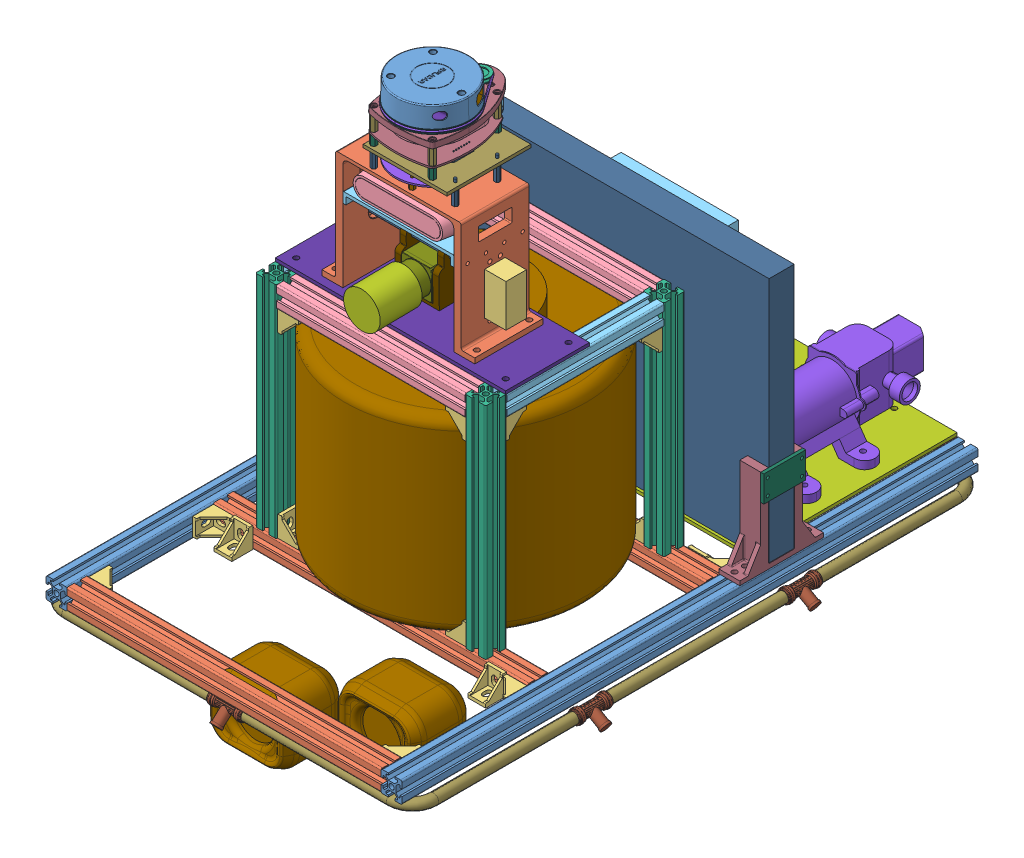
SolidWorks assembly 负载部分, configuration 默认. Lengths in mm.
Overall size (383.73 464.78 581.19).
141 component instances, 63 part files, 41 mates.
Components (placement in the parent):
- 外框架-1: 外框架 [默认] at (34.5366 78.9992 0) size (340 230 550)
  - 20x20-550mm-1: 20x20-550mm [默认] at (125.4634 0 -275) x (-1 0 0) z (0 0 -1) size (20 20 550)
  - 20x20-550mm-2: 20x20-550mm [默认] at (-194.5366 0 -275) x (-1 0 0) z (0 0 -1) size (20 20 550)
  - 20x20-300mm-1: 20x20-300mm [默认] at (115.4634 0 -265) x (0 0 -1) z (1 0 0) size (20 20 300)
  - 20x20-300mm-2: 20x20-300mm [默认] at (115.4634 0 265) x (0 0 -1) z (1 0 0) size (20 20 300)
  - 20x20-300mm-4: 20x20-300mm [默认] at (115.4634 0 125) x (0 0 -1) z (1 0 0) size (20 20 300)
  - 20x20-300mm-5: 20x20-300mm [默认] at (115.4634 0 -45) x (0 0 -1) z (1 0 0) size (20 20 300)
  - 2020 Corner pieces-1: 2020 Corner pieces [默认] at (55.4634 190 -44.8) x (0 0 1) z (0 -1 0) size (17 20 20)
  - 2020-210mm-1: 2020-210mm [默认] at (-124.5366 210 -45) x (0 0 1) z (-1 0 0) size (20 20 180)
  - 20x20-150mm-1: 20x20-150mm [默认] at (-134.5366 210 -35) x (0 1 0) z (0 0 -1) size (20 20 150)
  - 2020 Corner pieces-2: 2020 Corner pieces [默认] at (-124.5366 190 -44.8) x (0 0 -1) z (0 -1 0) size (17 20 20)
  - 2020 Corner pieces-3: 2020 Corner pieces [默认] at (-134.3366 190 -35) x (1 0 0) z (0 -1 0) size (17 20 20)
  - 2020 Corner pieces-4: 2020 Corner pieces [默认] at (-134.3366 190 115) x (-1 0 0) z (0 -1 0) size (17 20 20)
  - 2020 Corner pieces-5: 2020 Corner pieces [默认] at (-124.5366 190 125.2) x (0 0 -1) z (0 -1 0) size (17 20 20)
  - 2020-210mm-2: 2020-210mm [默认] at (-124.5366 210 125) x (0 0 1) z (-1 0 0) size (20 20 180)
  - 2020 Corner pieces-6: 2020 Corner pieces [默认] at (55.4634 190 125.2) x (0 0 1) z (0 -1 0) size (17 20 20)
  - 2020 Corner pieces-7: 2020 Corner pieces [默认] at (65.6634 190 115) x (-1 0 0) z (0 -1 0) size (17 20 20)
  - 20x20-150mm-2: 20x20-150mm [默认] at (65.4634 210 -35) x (0 1 0) z (0 0 -1) size (20 20 150)
  - 2020 Corner pieces-8: 2020 Corner pieces [默认] at (65.6634 190 -35) x (1 0 0) z (0 -1 0) size (17 20 20)
  - 2020 Corner pieces-9: 2020 Corner pieces [默认] at (45.4634 10 125.2) x (0 0 1) z (-1 0 0) size (17 20 20)
  - 2020 Corner pieces-10: 2020 Corner pieces [默认] at (45.4634 10 -44.8) x (0 0 1) z (-1 0 0) size (17 20 20)
  - 2020 Corner pieces-11: 2020 Corner pieces [默认] at (115.4634 -0.2 -65) x (0 -1 0) z (0 0 -1) size (17 20 20)
  - 2020 Corner pieces-12: 2020 Corner pieces [默认] at (-124.5366 20 125.2) x (0 0 1) z (0 1 0) size (17 20 20)
  - 2020 Corner pieces-13: 2020 Corner pieces [默认] at (115.4634 -0.2 145) x (0 1 0) z (0 0 1) size (17 20 20)
  - 2020 Corner pieces-14: 2020 Corner pieces [默认] at (-184.5366 -0.2 -65) x (0 1 0) z (0 0 -1) size (17 20 20)
  - 2020 Corner pieces-15: 2020 Corner pieces [默认] at (-124.5366 20 -44.8) x (0 0 1) z (0 1 0) size (17 20 20)
  - 2020 Corner pieces-16: 2020 Corner pieces [默认] at (-184.5366 -0.2 -245) x (0 -1 0) z (0 0 1) size (17 20 20)
  - 2020 Corner pieces-17: 2020 Corner pieces [默认] at (105.4634 0.2 -255) x (0 -1 0) z (-1 0 0) size (17 20 20)
  - 20x20-150mm-3: 20x20-150mm [默认] at (32.3019 210 -35) x (1 0 0) z (0 0 -1) size (20 20 150) (hidden)
  - 2020 Corner pieces-18: 2020 Corner pieces [默认] at (12.3019 209.8 115) x (0 1 0) z (-1 0 0) size (17 20 20)
  - 2020 Corner pieces-19: 2020 Corner pieces [默认] at (12.3019 209.8 -35) x (0 -1 0) z (-1 0 0) size (17 20 20) (hidden)
  - 20x20-150mm-4: 20x20-150mm [默认] at (-97.6981 210 -35) x (-1 0 0) z (0 0 -1) size (20 20 150) (hidden)
  - 2020 Corner pieces-20: 2020 Corner pieces [默认] at (-77.6981 210.2 115) x (0 -1 0) z (1 0 0) size (17 20 20)
  - 2020 Corner pieces-21: 2020 Corner pieces [默认] at (-77.6981 210.2 -35) x (0 1 0) z (1 0 0) size (17 20 20) (hidden)
  - 2020 Corner pieces-22: 2020 Corner pieces [默认] at (-155.5864 -10 -65) x (-1 0 0) z (0 0 -1) size (17 20 20)
  - 2020 Corner pieces-23: 2020 Corner pieces [默认] at (-155.5864 -10 145) size (17 20 20)
  - 2020 Corner pieces-24: 2020 Corner pieces [默认] at (86.8158 -10 145) size (17 20 20)
  - 2020 Corner pieces-25: 2020 Corner pieces [默认] at (-184.5366 -0.2 245) x (0 1 0) z (0 0 -1) size (17 20 20)
  - 2020 Corner pieces-26: 2020 Corner pieces [默认] at (105.4634 -0.2 255) x (0 1 0) z (-1 0 0) size (17 20 20)
  - 2020 Corner pieces-27: 2020 Corner pieces [默认] at (86.8158 -10 -65) x (-1 0 0) z (0 0 -1) size (17 20 20)
  - 2020 Corner pieces-28: 2020 Corner pieces [默认] at (-184.5366 0.2 145) x (0 -1 0) z (0 0 1) size (17 20 20)
  - 20x20-250mm-1: 20x20-250mm [默认] at (65.4634 220 125) x (0 0 -1) z (0 1 0) size (20 20 210)
  - 20x20-250mm-2: 20x20-250mm [默认] at (-134.5366 220 125) x (1 0 0) z (0 1 0) size (20 20 210)
  - 20x20-250mm-3: 20x20-250mm [默认] at (65.4634 220 -45) x (1 0 0) z (0 1 0) size (20 20 210)
  - 20x20-250mm-4: 20x20-250mm [默认] at (-134.5366 220 -45) x (1 0 0) z (0 1 0) size (20 20 210)
- 底板-1: 底板 [默认] at (0 88.9992 -175) size (300 3 200)
- 水泵-1: 水泵 [默认] at (88.6785 126.9992 -217.199) size (101.83 62 167)
- 圆形水箱5.5L-1: 圆形水箱5.5L [默认] at (0 88.9992 44.389) x (0.882387 0 0.470524) z (-0.470524 0 0.882387) size (230 205 230)
- 笔记本-1: 笔记本 [默认] at (0 210.9992 -100) size (339 235 24)
- 喷淋-1: 喷淋 [默认] at (0 63.9992 0) x (0 0 1) z (-1 0 0) size (573.75 26.49 383.73)
  - 喷头-1: 喷头 [默认] at (100 0 175) x (1 0 0) z (0 -0.777196 0.629259) size (36 13 23.5)
  - 皮管-1: 皮管 [默认] at origin size (550 10 360)
  - 喷头-2: 喷头 [默认] at (-270 0 0) x (0 0 1) z (-0.720565 -0.693388 0) size (36 13 23.5)
  - 喷头-3: 喷头 [默认] at (270 0 0) x (0 0 -1) z (0.744125 -0.66804 0) size (36 13 23.5)
  - 喷头-4: 喷头 [默认] at (100 0 -175) x (1 0 0) z (0 -0.496744 -0.867897) size (36 13 23.5)
  - 喷头-5: 喷头 [默认] at (-100 0 -175) x (1 0 0) z (0 -0.496744 -0.867897) size (36 13 23.5)
  - 喷头-6: 喷头 [默认] at (-100 0 175) x (1 0 0) z (0 -0.777196 0.629259) size (36 13 23.5)
- 笔记本架-1: 笔记本架 [默认] at (-160 88.9992 -87.5) x (-1 0 0) z (0 0 -1) size (20 84 80)
- 笔记本架-2: 笔记本架 [默认] at (160 88.9992 -87.5) size (20 84 80)
- 20x20-160mm-1: 20x20-160mm [默认] at (0 78.9992 -55) size (20 20 160)
- 2020 Corner pieces-1: 2020 Corner pieces [默认] at (10 78.9992 -65) x (0 1 0) z (0 0 -1) size (17 20 20)
- 2020 Corner pieces-2: 2020 Corner pieces [默认] at (-20 78.9992 -55) x (0 1 0) z (-1 0 0) size (17 20 20)
- 笔记本架侧挡板-1: 笔记本架侧挡板 [默认] at (170 160.4992 -87.5) x (0 0 -1) z (1 0 0) size (40 25 3)
- 笔记本架侧挡板-2: 笔记本架侧挡板 [默认] at (-170 160.4992 -87.5) x (0 0 1) z (-1 0 0) size (40 25 3)
- 传感器组合-1: 传感器组合 [默认] at (0 298.9992 76.0586) size (220 188.6 134.57)
  - MV-CE060-10UMUC-1: MV-CE060-10UMUC [默认] at (0 29.3441 9.6254) x (-1 0 0) z (0 0.015888 -0.999874) size (29.75 29.77 48.46)
  - 顶部连接板-1: 顶部连接板 [默认] at origin size (220 3 80)
  - 工业相机固定座-1: 工业相机固定座 [默认] at (0 12.0052 -0.6514) x (-1 0 0) z (0 0.015888 -0.999874) size (42 51 30)
  - 工业相机转轴-1: 工业相机转轴 [默认] at (-60.5 53 0) x (0 0.015888 -0.999874) z (1 0 0) size (20 20 95)
  - 激光雷达固定板-1: 激光雷达固定板 [默认] at (0 110 0) size (146 110 65)
  - MG995-1: MG995 [默认] at (80 43.15 0) x (0 1 0) z (0 0 1) size (54 43 19.5)
  - 摄像头D435-1: 摄像头D435 [默认] at (-0.0406 95.5 8.0001) x (0.999991 0 -0.004275) z (0 -1 0) size (90.1 25.01 25.72)
  - D345固定座-1: D345固定座 [默认] at (0 80 17.5) size (106 20 30)
  - 舵盘-1: 舵盘 [默认] at (34.5 53 0) x (0 0.015888 -0.999874) z (0 -0.999874 -0.015888) size (20 5 20)
  - 镜头-1: 镜头 [默认] at (0 29.2224 17.2844) x (0.876662 0.481046 0.007644) z (0.481107 -0.876551 -0.013928) size (35 50 35)
  - MicArrayV2.0-1: MicArrayV2.0 [默认] at (0 121 0) x (0 0 1) z (-1 0 0) size (72 6.8 70)
  - 铜柱2.5x8-1: 铜柱2.5x8 [默认] at (-19.9 113 -11.5) size (5.2 14 4.5)
  - 铜柱2.5x8-3: 铜柱2.5x8 [默认] at (7.77 113 27.1) x (0.840132 0 -0.542382) z (0.542382 0 0.840132) size (5.2 14 4.5)
  - 铜柱2.5x8-7: 铜柱2.5x8 [默认] at (19.9 113 -11.5) size (5.2 14 4.5)
  - 铜柱2.5x16-4: 铜柱2.5x16 [默认] at (-28 113 28) x (0.697872 0 -0.716222) z (0.716222 0 0.697872) size (5.2 22 4.5)
  - 铜柱2.5x16-8: 铜柱2.5x16 [默认] at (42 113 20) size (5.2 22 4.5)
  - 铜柱2.5x16-9: 铜柱2.5x16 [默认] at (42 113 -20) size (5.2 22 4.5)
  - 铜柱2.5x16-10: 铜柱2.5x16 [默认] at (-28 113 -28) size (5.2 22 4.5)
  - type-C接头-1: type-C接头 [默认] at (-56.8496 95.5012 11.493) x (0 -1 0) z (0.999991 0 -0.004275) size (12.5 6.5 48)
  - 顶部扩展-1: 顶部扩展 [默认] at (7 129 -7) size (80 3 80)
  - RPLIDAR A1 DevKit-2: RPLIDAR A1 DevKit [默认] at (13.0661 140.904 -69.4738) x (0 0 -1) z (1 0 0) size (102.81 56.6 71.78)
    - RPLIDAR A1 DevKit.igs-1: RPLIDAR A1 DevKit.igs [默认] at origin size (102.81 56.6 71.78)
      - 无线固定平台1.5.igs-1: 无线固定平台1.5.igs [默认] at (-69.4738 21.696 -13.0661) size (96.78 15.15 70.28)
      - 6807.igs-1: 6807.igs [默认] at (-69.4738 23.696 -13.0661) x (1 0 0) z (0 -1 0) size (47 47 7)
      - 无线旋转平台1.5.igs-1: 无线旋转平台1.5.igs [默认] at (-69.4738 25.696 -13.0661) x (0.00451 0 -0.99999) z (0.99999 0 0.00451) size (70.78 21.4 70.78)
      - 激光发射头.igs-1: 激光发射头.igs [默认] at (-94.6291 38.696 -19.9402) x (0.990886 0 -0.134705) z (0.134705 0 0.990886) size (6.5 6.5 21.2)
      - 激光导向槽1.5.igs-1: 激光导向槽1.5.igs [默认] at (-69.4738 29.696 -13.0661) x (-0.99999 0 -0.00451) z (0.00451 0 -0.99999) size (17.83 19.57 21.61)
      - 镜头导向槽1.5.igs-1: 镜头导向槽1.5.igs [默认] at (-69.4738 29.696 -13.0661) x (-0.99999 0 -0.00451) z (0.00451 0 -0.99999) size (22.09 19.65 24.8)
      - 圆台盖1.5.igs-1: 圆台盖1.5.igs [默认] at (-69.4738 47.696 -13.0661) x (0.99999 0 0.00451) z (0.00451 0 -0.99999) size (70 19.5 70)
      - 下隔磁片.igs-1: 下隔磁片.igs [默认] at (-69.4738 12.696 -13.0661) x (0.987093 0 -0.160146) z (0.160146 0 0.987093) size (25 1.2 25)
      - 发射PCB1.5.igs-1: 发射PCB1.5.igs [默认] at (-69.4738 11.696 -13.0661) size (55.5 1 57)
      - 底盖1.5.igs-1: 底盖1.5.igs [默认] at (-69.4738 10.696 -13.0661) size (60.21 11.34 60.96)
      - 电机.igs-1: 电机.igs [默认] at (-23.9738 2.196 -13.0661) x (0 0 -1) z (1 0 0) size (32 30.2 32)
      - 皮带轮1.5.igs-1: 皮带轮1.5.igs [默认] at (-23.9738 24.196 -13.0661) x (0.135455 0 -0.990784) z (0.990784 0 0.135455) size (18 5.5 18)
      - 镜头.igs-1: 镜头.igs [默认] at (-52.5259 38.696 -1.4895) x (0.136926 0.990581 0.000618) z (-0.00451 0 0.99999) size (14 14 11.5)
      - 皮带1-5^无线-RPLIDAR-1.5 DevKit.igs-1: 皮带1-5^无线-RPLIDAR-1.5 DevKit.igs [默认] at (-69.4738 26.196 -13.0661) x (1 0 0) z (0 -1 0) size (90.89 71.78 37.02)
      - 1.25 4pin.igs-1: 1.25 4pin.igs [默认] at (-45.3638 9.296 -13.0661) x (0 0 -1) z (0 -1 0) size (10.15 4.2 4.7)
      - 电机驱动板.igs-1: 电机驱动板.igs [默认] at (-23.9738 -1.404 -13.0661) x (-0.441218 0 -0.8974) z (0.8974 0 -0.441218) size (32 1.6 32)
      - 1.25 3pin.igs-1: 1.25 3pin.igs [默认] at (-36.9138 -3.104 -13.0661) x (0 0 1) z (0 -1 0) size (8.9 5.2 3.4)
      - 螺柱2.igs-1: 螺柱2.igs [默认] at (-97.4738 2.696 14.9339) size (5.77 15 5)
      - 螺柱2.igs-2: 螺柱2.igs [默认] at (-97.4738 2.696 -41.0661) size (5.77 15 5)
      - 螺柱2.igs-3: 螺柱2.igs [默认] at (-27.4738 2.696 -33.0661) size (5.77 15 5)
      - 螺柱2.igs-4: 螺柱2.igs [默认] at (-27.4738 2.696 6.9339) size (5.77 15 5)
      - 固定平台PCB.igs-1: 固定平台PCB.igs [默认] at (-69.4738 2.696 -13.0661) x (1 0 0) z (0 0 -1) size (80.7 4.7 70)
      - 7pin插槽.igs-1: 7pin插槽.igs [默认] at (-69.4738 1.096 14.0339) x (0 -1 0) z (1 0 0) size (8.2 5 20)
      - 螺柱1.igs-1: 螺柱1.igs [默认] at (-27.4738 -8.904 6.9339) size (5.77 10 5)
      - 螺柱1.igs-2: 螺柱1.igs [默认] at (-27.4738 -8.904 -33.0661) size (5.77 10 5)
      - 螺柱1.igs-3: 螺柱1.igs [默认] at (-97.4738 -8.904 14.9339) size (5.77 10 5)
      - 螺柱1.igs-4: 螺柱1.igs [默认] at (-97.4738 -8.904 -41.0661) size (5.77 10 5)
      - 1.25 3pin立贴.igs-1: 1.25 3pin立贴.igs [默认] at (-51.7938 0.996 -13.0661) x (0 0 1) z (1 0 0) size (8.8 4.7 4.36)
- 控制器V3.0-1: 控制器V3.0 [默认] at (-71 98.9992 -188.25) size (140 116 90)
  - 继电器-1: 继电器 [默认] at (-42.5 40 3) x (0 0 1) z (-1 0 0) size (50 16.5 25)
  - 控制板-1: 控制板 [默认] at (-12.5 44 6) x (0 0 1) z (1 0 0) size (44.5 4.5 17)
  - 铜柱2.5x14-1: 铜柱2.5x14 [默认] at (4.5 30 -33.25) x (0.992375 0 0.123257) z (0.123257 0 -0.992375) size (4.62 20 4)
  - 铜柱2.5x14-4: 铜柱2.5x14 [默认] at (4.5 16 -33.25) x (0.127193 0 -0.991878) z (-0.991878 0 -0.127193) size (4.62 20 4)
  - 铜柱2.5x8-1: 铜柱2.5x8 [默认] at (-52.5 32 -19.5) x (-0.890446 0 0.45509) z (-0.45509 0 -0.890446) size (5.2 14 4.5)
  - 铜柱2.5x8-2: 铜柱2.5x8 [默认] at (-32.5 32 25.5) x (0.068247 0 0.997668) z (-0.997668 0 0.068247) size (5.2 14 4.5)
  - 铜柱2.5x8-5: 铜柱2.5x8 [默认] at (-52.5 40 25.5) x (0.492798 0 0.870144) z (0.870144 0 -0.492798) size (5.2 14 4.5)
  - 铜柱2.5x8-9: 铜柱2.5x8 [默认] at (-32.5 32 -19.5) x (-0.892937 0 0.450182) z (-0.450182 0 -0.892937) size (5.2 14 4.5)
  - 底座-1: 底座 [默认] at (-12.5 32 -17.5) size (20 12 8)
  - 底座-2: 底座 [默认] at (-12.5 32 29.5) x (-1 0 0) z (0 0 -1) size (20 12 8)
  - 固定盖-1: 固定盖 [默认] at (-12.5 44 25.5) size (20 4.5 8)
  - 固定盖-2: 固定盖 [默认] at (-12.5 44 -13.5) x (-1 0 0) z (0 0 -1) size (20 4.5 8)
  - 电源降压模块-1: 电源降压模块 [默认] at origin size (115 27 76)
  - 锂电池-1: 锂电池 [默认] at (-55.2132 87 -8.1236) x (0 0 -1) z (0 -1 0) size (71 112 44)
  - 铜柱2.5x14-19: 铜柱2.5x14 [默认] at (4.5 16 33.25) x (0.870616 0 -0.491963) z (-0.491963 0 -0.870616) size (4.62 20 4)
  - 铜柱2.5x14-20: 铜柱2.5x14 [默认] at (4.5 30 33.25) x (0.925709 0 -0.378237) z (-0.378237 0 -0.925709) size (4.62 20 4)
  - 铜柱2.5x14-21: 铜柱2.5x14 [默认] at (-54.5 16 33.25) x (0.980795 0 -0.195041) z (0.195041 0 0.980795) size (4.62 20 4)
  - 铜柱2.5x14-22: 铜柱2.5x14 [默认] at (-54.5 2 33.25) x (0.655251 0 0.755411) z (-0.755411 0 0.655251) size (4.62 20 4)
  - 铜柱2.5x14-23: 铜柱2.5x14 [默认] at (-54.5 16 -33.25) x (-0.248568 0 0.968614) z (-0.968614 0 -0.248568) size (4.62 20 4)
  - 铜柱2.5x14-24: 铜柱2.5x14 [默认] at (-54.5 2 -33.25) x (0.655251 0 0.755411) z (-0.755411 0 0.655251) size (4.62 20 4)
  - 控制盒盖-1: 控制盒盖 [默认] at (0 65 -6.75) x (1 0 0) z (0 0 -1) size (120 8 90)
  - 固定板V3.0-2: 固定板V3.0 [默认] at (-25 32 0) x (1 0 0) z (0 0 -1) size (65 2 71)
  - 外壳-2: 外壳 [默认] at (0 -7 -6.75) x (-1 0 0) z (0 0 -1) size (140 70 90)
- 音箱-1: 音箱 [默认] at (107.2497 43.1344 212.1639) size (78 64 55.7)
- 音箱-2: 音箱 [默认] at (12.6 22.8179 239.2478) size (78 64 55.7)
Mates (geometry in assembly coordinates):
- 重合9: coincident anti-aligned: plane of 外框架-1/20x20-300mm-5 through (-150 88.9992 -48.1) normal (0 1 0); plane of 底板-1 through (0 88.9992 -175) normal (0 -1 0)
- 重合13: coincident anti-aligned: plane of 外框架-1/20x20-550mm-1 through (150 82.0992 275) normal (-1 0 0); plane of 底板-1 through (150 91.9992 -275) normal (1 0 0)
- 重合14: coincident aligned: plane of 底板-1 through (-150 91.9992 -275) normal (0 0 -1); plane of 外框架-1/20x20-300mm-1 through (-150 82.0992 -275) normal (0 0 -1)
- 重合15: coincident anti-aligned: plane of 外框架-1/20x20-300mm-4 through (-150 88.9992 121.9) normal (0 1 0); plane of 圆形水箱5.5L-1 through (0 88.9992 44.389) normal (0 -1 0)
- 相切3: tangent anti-aligned: cylinder of 外框架-1/20x20-250mm-2 through (-91.5 88.9992 116.5) axis (0 1 0) radius 1.5; cylinder of 圆形水箱5.5L-1 through (0 268.9992 44.389) axis (0 -1 0) radius 115
- 重合26: coincident anti-aligned: plane of 底板-1 through (0 91.9992 -175) normal (0 1 0); plane of 水泵-1 through (114.5926 91.9992 -197.199) normal (0 -1 0)
- 重合35: coincident anti-aligned: plane of 喷淋-1 through (0 63.9992 0) normal (-1 0 0)
- 重合36: coincident aligned: plane of 喷淋-1 through (0 63.9992 0) normal (0 0 1)
- 相切7: tangent anti-aligned: plane of 外框架-1/20x20-550mm-1 through (168.5 68.9992 275) normal (0 -1 0); cylinder of 喷淋-1/皮管-1 through (155 63.9992 -270) axis (-1 0 0) radius 5
- 相切8: tangent anti-aligned: cylinder of 外框架-1/20x20-250mm-1 through (91.5 88.9992 116.5) axis (0 1 0) radius 1.5; cylinder of 圆形水箱5.5L-1 through (0 268.9992 44.389) axis (0 -1 0) radius 115
- 重合38: coincident aligned: plane of 笔记本架-1 through (-150 172.9992 -67.5) normal (0 0 1); plane of 笔记本架-2 through (150 172.9992 -67.5) normal (0 0 1)
- 重合39: coincident anti-aligned: plane of 笔记本-1 through (0 210.9992 -100) normal (0 0 -1); plane of 笔记本架-1 through (-170 172.9992 -100) normal (0 0 1)
- 重合42: coincident anti-aligned: plane of 笔记本-1 through (-169.5 93.4992 -76) normal (0 -1 0); plane of 笔记本架-2 through (170 93.4992 -100) normal (0 1 0)
- 重合44: coincident anti-aligned: plane of 20x20-160mm-1 through (-10 82.0992 -215) normal (-1 0 0); plane of 2020 Corner pieces-2 through (-10 70.4992 -75) normal (1 0 0)
- 重合45: coincident aligned: plane of 20x20-160mm-1 through (8.5 70.4992 -55) normal (0 0 1); plane of 2020 Corner pieces-2 through (-20 78.9992 -55) normal (0 0 1)
- 重合46: coincident anti-aligned: plane of 20x20-160mm-1 through (10 82.0992 -215) normal (1 0 0); plane of 2020 Corner pieces-1 through (10 78.9992 -65) normal (-1 0 0)
- 重合47: coincident aligned: plane of 20x20-160mm-1 through (8.5 70.4992 -55) normal (0 0 1); plane of 2020 Corner pieces-1 through (30 70.4992 -55) normal (0 0 1)
- 重合48: coincident aligned: plane of 2020 Corner pieces-1 through (30 87.4992 -75) normal (0 1 0); plane of 2020 Corner pieces-2 through (-30 87.4992 -75) normal (0 1 0)
- 宽度6: width aligned: plane of 20x20-160mm-1 through (-8.5 88.9992 -215) normal (0 1 0); plane of 2020 Corner pieces-2 through (-8.5 68.9992 -215) normal (0 -1 0); plane of 20x20-160mm-1 through (-30 87.4992 -75) normal (0 1 0); plane of 2020 Corner pieces-2 through (-30 70.4992 -75) normal (0 -1 0)
- 重合49: coincident anti-aligned: plane of 外框架-1/20x20-300mm-5 through (-150 82.0992 -55) normal (0 0 -1); plane of 20x20-160mm-1 through (8.5 70.4992 -55) normal (0 0 1)
- 重合50: coincident aligned: plane of 外框架-1/20x20-300mm-5 through (-150 88.9992 -48.1) normal (0 1 0); plane of 20x20-160mm-1 through (-8.5 88.9992 -215) normal (0 1 0)
- 宽度7: width anti-aligned: plane of 外框架-1/20x20-300mm-1 through (-150 70.4992 -273.5) normal (-1 0 0); plane of 20x20-160mm-1 through (150 70.4992 -273.5) normal (1 0 0); plane of 外框架-1/20x20-300mm-1 through (10 70.4992 -215) normal (1 0 0); plane of 20x20-160mm-1 through (-10 70.4992 -215) normal (-1 0 0)
- 重合51: coincident anti-aligned: plane of 外框架-1/20x20-550mm-1 through (156.9 88.9992 275) normal (0 1 0); plane of 笔记本架-2 through (160 88.9992 -87.5) normal (0 -1 0)
- 宽度8: width aligned: plane of 外框架-1/20x20-550mm-1 through (170 82.0992 275) normal (1 0 0); plane of 外框架-1/20x20-550mm-1 through (150 82.0992 275) normal (-1 0 0); plane of 笔记本架-2 through (170 92.9992 -127.5) normal (1 0 0); plane of 笔记本架-2 through (150 92.9992 -127.5) normal (-1 0 0)
- 宽度9: width aligned: plane of 外框架-1/20x20-550mm-2 through (-170 82.0992 275) normal (-1 0 0); plane of 外框架-1/20x20-550mm-2 through (-150 82.0992 275) normal (1 0 0); plane of 笔记本架-1 through (-170 92.9992 -47.5) normal (-1 0 0); plane of 笔记本架-1 through (-150 92.9992 -47.5) normal (1 0 0)
- 重合52: coincident anti-aligned: plane of 笔记本-1 through (-169.5 93.4992 -76) normal (0 -1 0); plane of 笔记本架-1 through (-170 93.4992 -75) normal (0 1 0)
- 宽度10: width anti-aligned: plane of 笔记本架-2 through (170 92.9992 -127.5) normal (1 0 0); plane of 笔记本架-1 through (-170 92.9992 -47.5) normal (-1 0 0); plane of 笔记本-1 through (-169.5 328.4992 -76) normal (-1 0 0); plane of 笔记本-1 through (169.5 328.4992 -76) normal (1 0 0)
- 同心16: concentric aligned: cylinder of 笔记本架-2 through (170 167.9992 -71.25) axis (-1 0 0) radius 1.25; cylinder of 笔记本架侧挡板-1 through (173 167.9992 -71.25) axis (-1 0 0) radius 1.5
- 同心17: concentric aligned: cylinder of 笔记本架-2 through (170 152.9992 -71.25) axis (-1 0 0) radius 1.25; cylinder of 笔记本架侧挡板-1 through (173 152.9992 -71.25) axis (-1 0 0) radius 1.5
- 重合53: coincident anti-aligned: plane of 笔记本架-2 through (170 92.9992 -127.5) normal (1 0 0); plane of 笔记本架侧挡板-1 through (170 160.4992 -87.5) normal (-1 0 0)
- 同心18: concentric aligned: cylinder of 笔记本架-1 through (-170 167.9992 -103.75) axis (1 0 0) radius 1.25; cylinder of 笔记本架侧挡板-2 through (-173 167.9992 -103.75) axis (1 0 0) radius 1.5
- 同心19: concentric aligned: cylinder of 笔记本架-1 through (-170 152.9992 -103.75) axis (1 0 0) radius 1.25; cylinder of 笔记本架侧挡板-2 through (-173 152.9992 -103.75) axis (1 0 0) radius 1.5
- 重合54: coincident anti-aligned: plane of 笔记本架-1 through (-170 92.9992 -47.5) normal (-1 0 0); plane of 笔记本架侧挡板-2 through (-170 160.4992 -87.5) normal (1 0 0)
- 重合55: coincident anti-aligned: plane of 外框架-1/20x20-150mm-2 through (91.5 298.9992 115) normal (0 1 0); plane of 传感器组合-1/顶部连接板-1 through (0 298.9992 76.0586) normal (0 -1 0)
- 重合56: coincident aligned: plane of 外框架-1/20x20-150mm-1 through (-110 292.0992 115) normal (-1 0 0); plane of 传感器组合-1/顶部连接板-1 through (-110 301.9992 36.0586) normal (-1 0 0)
- 重合57: coincident anti-aligned: plane of 底板-1 through (0 91.9992 -175) normal (0 1 0); plane of 控制器V3.0-1/外壳-2 through (-71 91.9992 -195) normal (0 -1 0)
- 同心20: concentric anti-aligned: cylinder of 底板-1 through (-136 88.9992 -155) axis (0 1 0) radius 1.5; cylinder of 控制器V3.0-1/外壳-2 through (-136 94.9992 -155) axis (0 -1 0) radius 1.6
- 同心21: concentric anti-aligned: cylinder of 底板-1 through (-136 88.9992 -235) axis (0 1 0) radius 1.5; cylinder of 控制器V3.0-1/外壳-2 through (-136 94.9992 -235) axis (0 -1 0) radius 1.6
- 距离1: distance = 27.199 mm anti-aligned: plane of 笔记本-1 through (0 210.9992 -100) normal (0 0 -1); plane of 水泵-1 through (88.6785 126.9992 -127.199) normal (0 0 1)
- 距离2: distance = 79.6785 mm anti-aligned: plane of 水泵-1 through (68.6785 150.9992 -251.199) normal (-1 0 0); plane of 控制器V3.0-1/外壳-2 through (-11 161.9992 -150) normal (1 0 0)
- 重合61: coincident: line of 外框架-1/2020 Corner pieces-11 through (147 87.2992 -75) axis (1 0 0); plane of 笔记本架-2 through (170 172.9992 -75) normal (0 0 -1)
